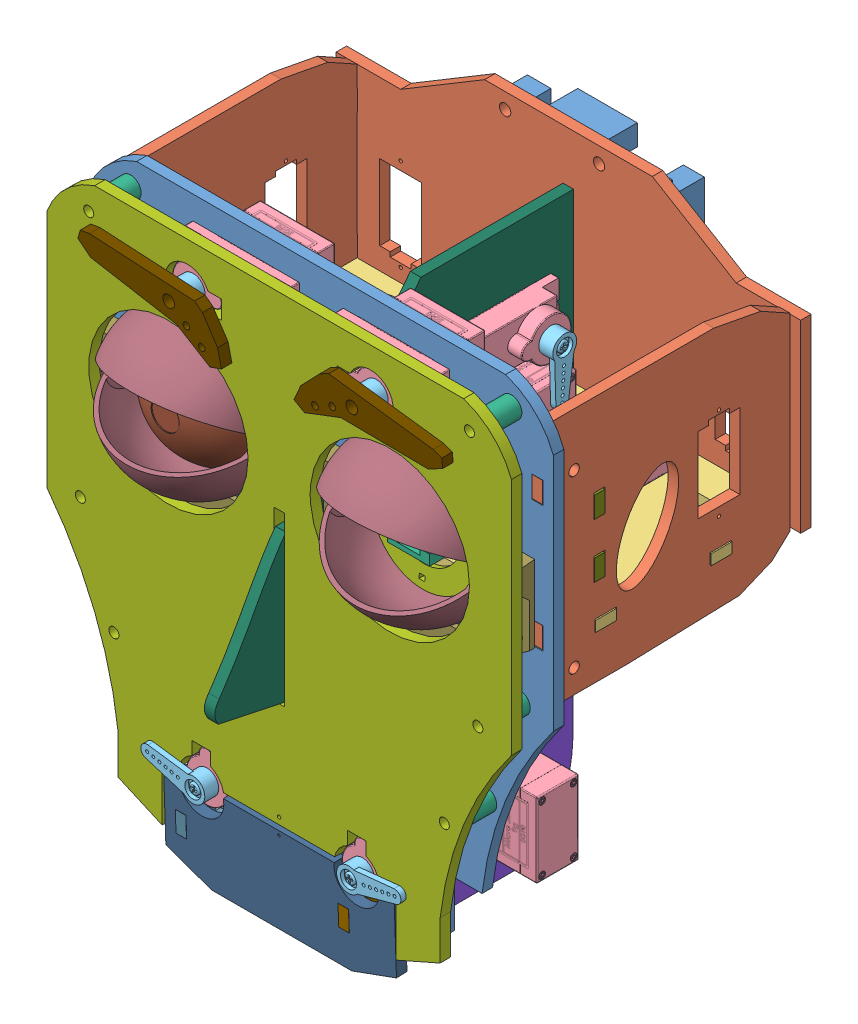
SolidWorks assembly Assembly_skullbox, configuration Default. Lengths in mm.
Overall size (140.72 167.86 124.87).
78 component instances, 31 part files, 174 mates.
Components (placement in the parent):
- faceFrameBack-1: faceFrameBack [Default] at (-18.3406 54.7458 -27.5154) size (140.72 156.7 3.18)
- skullbox_side-1: skullbox_side [Default] at (-85.5236 10.1688 -63.3929) size (3.18 75.04 78.21)
- skullbox_bottom-1: skullbox_bottom [Default] at (-18.3406 -15.2312 -64.0914) size (134.47 3.18 65.53)
- SG90 BODY-1: SG90 BODY [Default] at (-44.9852 -5.3125 -69.5016) x (0 0 1) z (-1 0 0) size (32.36 29.6 12.65)
- SG90 ARM-1: SG90 ARM [Default] at (-51.2844 1.5836 -75.8008) x (0.999363 0 -0.035696) z (0.035696 0 0.999363) size (19.74 4.23 7.24)
- SG90 BODY-2: SG90 BODY [Default] at (-34.4188 -5.3125 -64.2438) size (32.36 29.6 12.65)
- SG90 ARM-2: SG90 ARM [Default] at (-40.718 1.5836 -57.9446) x (0.976821 0 -0.214059) z (0.214059 0 0.976821) size (19.74 4.23 7.24)
- spacer_#6thread_3_4trlong-1: spacer_#6thread_3_4trlong [93330A443] at (-75.9986 47.1258 -19.5779) x (0.813395 0.581711 0) z (0 0 1) size (6.35 6.35 10.62)
- spacer_#6thread_3_4trlong-2: spacer_#6thread_3_4trlong [93330A443] at (-68.3786 -59.5542 -19.5779) size (6.35 6.35 10.62)
- spacer_#6thread_3_4trlong-3: spacer_#6thread_3_4trlong [93330A443] at (39.3174 47.1258 -19.5779) size (6.35 6.35 10.62)
- spacer_#6thread_3_4trlong-4: spacer_#6thread_3_4trlong [93330A443] at (31.6974 -59.5542 -19.5779) x (-0.161594 -0.986857 0) z (0 0 1) size (6.35 6.35 10.62)
- faceFrameFront-1: faceFrameFront [Default] at (-18.3406 54.7458 -14.8154) size (140.72 157.48 3.18)
- spacer_#6thread_3_4trlong-5: spacer_#6thread_3_4trlong [93330A443] at (41.8574 -29.0742 -19.5779) size (6.35 6.35 10.62)
- spacer_#6thread_3_4trlong-6: spacer_#6thread_3_4trlong [93330A443] at (-78.5386 -29.0742 -19.5779) size (6.35 6.35 10.62)
- SG90 BODY-4: SG90 BODY [Default] at (-52.3824 35.0825 -17.5967) x (-1 0.000928 0) z (0.000928 1 0) size (32.36 29.6 12.65)
- skullBoxMandible-3: skullBoxMandible [Default] at (13.4602 -65.9042 -46.5654) size (3.18 63.5 41.33)
- SG90 BODY-5: SG90 BODY [Default] at (6.7165 -91.99 -42.222) x (0 -1 0) z (0 0 -1) size (32.36 29.6 12.65)
- SG90 ARM-3: SG90 ARM [Default] at (-0.7384 -85.6908 -48.5212) x (0 0.917715 0.397239) z (0 -0.397239 0.917715) size (19.74 4.23 7.24)
- jawbone3-1: jawbone3 [Default] at (-0.7384 -85.6908 -48.5212) x (1 0 0) z (0 -0.034208 0.999415) size (3.18 31.5 43.99)
- jawFront-1: jawFront [Default] at (-18.382 -95.8718 -15.0679) x (1 0 0) z (0 -0.034208 0.999415) size (69.85 26.67 3.17)
- skullbox_side-2: skullbox_side [Default] at (45.6166 10.4228 -63.3929) size (3.18 75.04 78.21)
- SG90 BODY-7: SG90 BODY [Default] at (-26.6972 -9.0082 -87.6372) x (0 0 -1) z (0 1 0) size (32.36 29.6 12.65)
- SG90 ARM-5: SG90 ARM [Default] at (-33.5933 -2.709 -81.338) x (0 -0.999683 0.025167) z (0 -0.025167 -0.999683) size (19.74 4.23 7.24)
- SG90 BODY-8: SG90 BODY [Default] at (-10.0348 20.1002 -87.6372) x (0 0 -1) z (0 -1 0) size (32.36 29.6 12.65)
- SG90 ARM-6: SG90 ARM [Default] at (-3.1387 13.801 -81.338) x (0 0.998641 -0.052121) z (0 -0.052121 -0.998641) size (19.74 4.23 7.24)
- skullBoxMandibleRight-3: skullBoxMandibleRight [Default] at (-53.2656 -65.9042 -46.5654) size (3.18 63.5 41.33)
- jawCrossBeam-2: jawCrossBeam [Default] at (-23.7889 -100.3419 -40.0004) x (1 0 0) z (0 -0.034208 0.999415) size (52.55 11.43 3.17)
- mandibleBack-2: mandibleBack [Default] at (-18.3406 -51.2992 -62.3896) size (69.95 34.29 3.18)
- SG90 BODY-9: SG90 BODY [Default] at (11.5298 -92.5742 -17.5967) x (0 -1 0) z (-1 0 0) size (32.36 29.6 12.65)
- SG90 ARM-7: SG90 ARM [Default] at (5.2306 -86.275 -10.7006) x (-0.983188 -0.182597 0) z (-0.182597 0.983188 0) size (19.74 4.23 7.24)
- jawboneRight-1: jawboneRight [Default] at (-50.0144 -85.6908 -48.5212) x (1 0 0) z (0 -0.034208 0.999415) size (3.17 31.94 43.99)
- SG90 BODY-10: SG90 BODY [Default] at (-35.6126 -92.5742 -17.5967) x (0 -1 0) z (-1 0 0) size (32.36 29.6 12.65)
- SG90 ARM-8: SG90 ARM [Default] at (-41.9118 -86.275 -10.7006) x (0.976458 -0.215708 0) z (-0.215708 -0.976458 0) size (19.74 4.23 7.24)
- skullBoxNosePanel-1: skullBoxNosePanel [Default] at (-19.9535 13.3438 -63.5199) size (3.18 90.94 112.09)
- skullbox_firewall-1: skullbox_firewall [Default] at (-18.2771 6.9938 -43.0602) size (134.37 41.33 3.18)
- angleBracket_4_40screwThread-1: angleBracket_4_40screwThread [Default] at (41.1335 30.6132 -27.5154) x (0.999994 -0.003567 0) z (0 0 -1) size (8.71 6.35 9.53)
- angleBracket_4_40screwThread-2: angleBracket_4_40screwThread [Default] at (-77.8147 30.6158 -27.5154) x (-1 0 0) z (0 0 -1) size (8.71 6.35 9.53)
- angleBracket_4_40screwThread-3: angleBracket_4_40screwThread [Default] at (41.1335 -21.4542 -27.5154) x (1 0 0) z (0 0 -1) size (8.71 6.35 9.53)
- angleBracket_4_40screwThread-4: angleBracket_4_40screwThread [Default] at (-77.8147 -21.4542 -27.5154) x (-1 0 0) z (0 0 -1) size (8.71 6.35 9.53)
- angleBracket_4_40screwThread-5: angleBracket_4_40screwThread [Default] at (20.9913 -50.6642 -27.5154) x (-1 0 0) z (0 0 -1) size (8.71 6.35 9.53)
- angleBracket_4_40screwThread-6: angleBracket_4_40screwThread [Default] at (-57.6725 -50.6642 -27.5154) x (1 0 0) z (0 0 -1) size (8.71 6.35 9.53)
- SG90 BODY-11: SG90 BODY [Default] at (15.6896 47.5793 -17.5967) x (1 0.000928 0) z (0.000928 -1 0) size (32.36 29.6 12.65)
- SG90 ARM-9: SG90 ARM [Default] at (-46.0773 41.3759 -10.7006) x (-0.81658 0.577232 0) z (0.577232 0.81658 0) size (19.74 4.23 7.24)
- SG90 ARM-10: SG90 ARM [Default] at (9.3963 41.2743 -10.7006) x (0.907777 0.419454 0) z (0.419454 -0.907777 0) size (19.74 4.23 7.24)
- eyebrow-1: eyebrow [Default] at (-51.4817 40.5048 -9.0877) x (0.960868 -0.277008 0) z (0 0 1) size (45.26 13.1 3.17)
- eyebrow-2: eyebrow [Default] at (14.5528 39.4369 -5.9127) x (-0.995184 -0.098029 0) z (0 0 -1) size (45.26 13.1 3.17)
- unoKitBoard-1: unoKitBoard [Default] at (-18.3181 17.1284 -102.4454) x (0 1 0) z (0 0 -1) size (72.06 53.59 12.95)
- skullbox_back-2: skullbox_back [Default] at (-18.3406 10.8038 -102.4454) size (140.72 79.4 3.18)
- gearLargeB-1: gearLargeB [Default] at (-62.9176 -70.1452 -73.0314) x (0 0 1) z (-1 0 0) size (48.61 57.77 3.18)
- gearLargeNoTabs-1: gearLargeNoTabs [Default] at (-59.7426 -70.1452 -73.0314) x (0 0 1) z (-1 0 0) size (45.38 54.54 3.17)
- spacerNeckTilt-1: spacerNeckTilt [Default] at (-59.7426 -42.4092 -45.2954) size (3.17 25.4 25.4)
- gearLargeNoTabs-2: gearLargeNoTabs [Default] at (-66.0926 -70.1452 -73.0314) x (0 0 1) z (-1 0 0) size (45.38 54.54 3.17)
- Assembly_eyeWithStraighPullParts-3: Assembly_eyeWithStraighPullParts [Default] at (-52.8322 6.1704 -29.3385) x (-1 0 0) z (0 0 1) size (36.66 36.54 29.79)
  - eyeBracket_straightPull-1: eyeBracket_straightPull [Default] at (-1.0272 -6.7924 0.7563) size (19.05 12.95 22.61)
  - eyeRing_straightPull-1: eyeRing_straightPull [Default] at (-1.1034 -0.1884 5.7083) x (0.999925 0 0.012279) z (-0.012279 -0.002177 0.999922) size (33.02 35.56 7.15)
  - clevisPin_cored-1: clevisPin_cored [Default] at (-1.0272 -8.1259 5.7093) x (0.999925 0 0.012279) z (0 1 0) size (9.65 9.65 18.35)
  - eyeXAxisRod-1: eyeXAxisRod [Default] at (-17.6121 -0.1884 5.5056) x (0.999925 0 0.012279) z (-0.012279 0 0.999925) size (33.02 2.34 2.34)
  - spacer_1_4trlong-1: spacer_1_4trlong [94639A705] at (5.6017 -0.1884 5.7907) x (-0.004447 -0.932122 0.362118) z (-0.999925 0 -0.012279) size (4.76 4.76 6.91)
  - spacer_1_4trlong-2: spacer_1_4trlong [94639A705] at (-7.8085 -0.1884 5.626) x (-0.012279 0 0.999925) z (-0.999925 0 -0.012279) size (4.76 4.76 6.91)
  - eye-1: eye [Default] at (-1.1131 -0.1901 6.502) x (0.999701 0.021124 0.012322) z (-0.012279 -0.002177 0.999922) size (35.76 35.76 12.49)
- SG90 BODY-12: SG90 BODY [Default] at (-2.5926 -5.3125 -51.747) x (-1 0 0) z (0 0 -1) size (32.36 29.6 12.65)
- SG90 BODY-13: SG90 BODY [Default] at (20.8008 -5.3125 -69.1714) x (0 0 1) z (-1 0 0) size (32.36 29.6 12.65)
- SG90 ARM-11: SG90 ARM [Default] at (3.7066 1.5836 -58.0462) x (-0.998428 0 -0.05604) z (0.05604 0 -0.998428) size (19.74 4.23 7.24)
- SG90 ARM-12: SG90 ARM [Default] at (14.5016 1.5836 -75.4706) x (-0.999964 0 -0.008467) z (0.008467 0 -0.999964) size (19.74 4.23 7.24)
- spacer_1_4trlong-1: spacer_1_4trlong [94639A705] at (8.4722 6.6128 -23.8353) x (-0.030396 0 0.999538) z (-0.999538 0 -0.030396) size (4.76 4.76 6.91)
- eyeBracket_straightPull-1: eyeBracket_straightPull [Default] at (15.2509 0.0088 -28.5822) size (19.05 12.95 22.61)
- eyeRing_straightPull-1: eyeRing_straightPull [Default] at (15.1748 6.6128 -23.6315) x (0.999538 0 0.030396) z (-0.030272 0.090239 0.99546) size (33.02 35.56 7.15)
- clevisPin_cored-1: clevisPin_cored [Default] at (15.2509 -1.3247 -23.6292) x (0.999538 0 0.030396) z (0 1 0) size (9.65 9.65 18.35)
- eyeXAxisRod-1: eyeXAxisRod [Default] at (-1.3276 6.6128 -24.1334) x (0.999538 0 0.030396) z (-0.030396 0 0.999538) size (33.02 2.34 2.34)
- spacer_1_4trlong-2: spacer_1_4trlong [94639A705] at (21.8773 6.6128 -23.4277) x (-0.030396 0 0.999538) z (-0.999538 0 -0.030396) size (4.76 4.76 6.91)
- eye-1: eye [Default] at (15.1507 6.6844 -22.8414) x (-0.843364 -0.536849 0.023019) z (-0.030272 0.090239 0.99546) size (35.76 35.76 12.49) (hidden)
- Assembly_Eyelid_StraightPullParts-1: Assembly_Eyelid_StraightPullParts [Default] at (-51.0341 -8.3385 -21.5988) size (62.38 64.85 38.25)
  - eyeLidMount_B-1: eyeLidMount_B [Default] at (-0.8344 -17.1797 -2.7416) x (-1 0 0) z (0 0 1) size (62.38 36.2 5.33)
  - eyelidA-2: eyelidA [Default] at (-1.4136 14.8243 0.4334) x (0 0.463125 0.886293) z (-1 0 0) size (27.73 27.4 48.41)
  - eyelidA-3: eyelidA [Default] at (-1.1646 14.8243 0.4334) x (0 -0.332285 0.943179) z (1 0 0) size (27.73 27.4 48.41)
- eyeLidMount_B-1: eyeLidMount_B [Default] at (15.1874 -25.5182 -24.3404) x (-1 0 0) z (0 0 1) size (62.38 36.2 5.33)
- eyelidA-1: eyelidA [Default] at (14.6083 6.4858 -21.1654) x (0 0.456477 0.889735) z (-1 0 0) size (27.73 27.4 48.41)
- eyelidA-2: eyelidA [Default] at (14.8572 6.4858 -21.1654) x (0 -0.518383 0.855148) z (1 0 0) size (27.73 27.4 48.41)
Mates (geometry in assembly coordinates):
- Coincident15: coincident anti-aligned: plane of skullbox_bottom-1 through (-57.5836 -15.2313 -92.0314) normal (1 0 0); plane of SG90 BODY-1 through (-57.5836 -5.3125 -69.5016) normal (-1 0 0)
- Coincident16: coincident anti-aligned: plane of skullbox_bottom-1 through (-44.8836 -15.2313 -92.0314) normal (0 0 1); plane of SG90 BODY-1 through (-57.5836 -27.8169 -92.0314) normal (0 0 -1)
- Coincident17: coincident anti-aligned: plane of skullbox_bottom-1 through (45.6674 -12.0562 -94.3174) normal (0 1 0); plane of SG90 BODY-1 through (-57.5836 -12.0562 -64.5867) normal (0 -1 0)
- Concentric11: concentric aligned: cylinder of SG90 BODY-1 through (-51.2844 37.8563 -75.8008) axis (0 -1 0) radius 2.286; cylinder of SG90 ARM-1 through (-51.2844 1.3042 -75.8008) axis (0 -1 0) radius 2.286
- Coincident18: coincident anti-aligned: plane of SG90 BODY-1 through (-57.5836 -1.0326 -69.5016) normal (0 1 0); plane of SG90 ARM-1 through (-51.2844 -1.0326 -75.8008) normal (0 -1 0)
- Coincident19: coincident anti-aligned: plane of skullbox_bottom-1 through (-56.9486 -15.2313 -51.6454) normal (0 0 -1); plane of SG90 BODY-2 through (-34.4188 -5.3125 -51.6454) normal (0 0 1)
- Coincident20: coincident anti-aligned: plane of skullbox_bottom-1 through (-56.9486 -15.2313 -64.3454) normal (1 0 0); plane of SG90 BODY-2 through (-56.9486 -27.8169 -51.6454) normal (-1 0 0)
- Coincident21: coincident anti-aligned: plane of skullbox_bottom-1 through (45.6674 -12.0562 -94.3174) normal (0 1 0); plane of SG90 BODY-2 through (-29.5039 -12.0562 -51.6454) normal (0 -1 0)
- Concentric12: concentric aligned: cylinder of SG90 BODY-2 through (-40.718 37.8563 -57.9446) axis (0 -1 0) radius 2.286; cylinder of SG90 ARM-2 through (-40.718 1.3042 -57.9446) axis (0 -1 0) radius 2.286
- Coincident22: coincident anti-aligned: plane of SG90 BODY-2 through (-34.4188 -1.0326 -51.6454) normal (0 1 0); plane of SG90 ARM-2 through (-40.718 -1.0326 -57.9446) normal (0 -1 0)
- Coincident29: coincident anti-aligned: plane of faceFrameBack-1 through (-85.5236 26.0438 -27.5154) normal (0 1 0); plane of skullbox_side-1 through (-82.3486 26.0438 -24.2896) normal (0 -1 0)
- Coincident30: coincident anti-aligned: plane of faceFrameBack-1 through (-85.5236 26.0438 -27.5154) normal (1 0 0); plane of skullbox_side-1 through (-85.5236 38.7438 -27.5154) normal (-1 0 0)
- Coincident31: coincident anti-aligned: plane of faceFrameBack-1 through (-88.6986 -84.9542 -27.5154) normal (0 0 -1); plane of skullbox_side-1 through (-82.3486 -18.4062 -27.5154) normal (0 0 1)
- Concentric13: concentric aligned: cylinder of faceFrameBack-1 through (-75.9986 47.1258 -27.5154) axis (0 0 1) radius 1.524; cone of spacer_#6thread_3_4trlong-1 through (-75.9986 47.1258 -24.3404) axis (0 0 1)
- Coincident35: coincident anti-aligned: plane of faceFrameBack-1 through (-88.6986 -84.9542 -24.3404) normal (0 0 1); plane of spacer_#6thread_3_4trlong-1 through (-75.9986 47.1258 -24.3404) normal (0 0 -1)
- Concentric14: concentric anti-aligned: cylinder of faceFrameBack-1 through (-68.3786 -59.5542 -27.5154) axis (0 0 1) radius 1.524; circle of spacer_#6thread_3_4trlong-2
- Coincident36: coincident anti-aligned: plane of faceFrameBack-1 through (-88.6986 -84.9542 -24.3404) normal (0 0 1); plane of spacer_#6thread_3_4trlong-2 through (-68.3786 -59.5542 -24.3404) normal (0 0 -1)
- Concentric15: concentric anti-aligned: cylinder of faceFrameBack-1 through (31.6974 -59.5542 -27.5154) axis (0 0 1) radius 1.524; circle of spacer_#6thread_3_4trlong-4
- Coincident37: coincident anti-aligned: plane of faceFrameBack-1 through (-88.6986 -84.9542 -24.3404) normal (0 0 1); plane of spacer_#6thread_3_4trlong-4 through (31.6974 -59.5542 -24.3404) normal (0 0 -1)
- Concentric16: concentric anti-aligned: cylinder of faceFrameBack-1 through (39.3174 47.1258 -27.5154) axis (0 0 1) radius 1.524; circle of spacer_#6thread_3_4trlong-3
- Coincident38: coincident anti-aligned: plane of faceFrameBack-1 through (-88.6986 -84.9542 -24.3404) normal (0 0 1); plane of spacer_#6thread_3_4trlong-3 through (39.3174 47.1258 -24.3404) normal (0 0 -1)
- Concentric17: concentric anti-aligned: circle of spacer_#6thread_3_4trlong-3; cylinder of faceFrameFront-1 through (39.3174 47.1258 -14.8154) axis (0 0 1) radius 1.524
- Coincident39: coincident anti-aligned: plane of spacer_#6thread_3_4trlong-3 through (39.3174 47.1258 -14.8154) normal (0 0 1); plane of faceFrameFront-1 through (-88.6986 -84.9542 -14.8154) normal (0 0 -1)
- Concentric18: concentric anti-aligned: circle of spacer_#6thread_3_4trlong-4; cylinder of faceFrameFront-1 through (31.6974 -59.5542 -14.8154) axis (0 0 1) radius 1.524
- Concentric19: concentric anti-aligned: cylinder of faceFrameFront-1 through (-78.5386 -29.0742 -14.8154) axis (0 0 1) radius 1.524; circle of spacer_#6thread_3_4trlong-6
- Coincident40: coincident anti-aligned: plane of faceFrameFront-1 through (-88.6986 -84.9542 -14.8154) normal (0 0 -1); plane of spacer_#6thread_3_4trlong-6 through (-78.5386 -29.0742 -14.8154) normal (0 0 1)
- Concentric20: concentric anti-aligned: cylinder of faceFrameBack-1 through (41.8574 -29.0742 -27.5154) axis (0 0 1) radius 1.524; circle of spacer_#6thread_3_4trlong-5
- Coincident41: coincident anti-aligned: plane of faceFrameBack-1 through (-88.6986 -84.9542 -24.3404) normal (0 0 1); plane of spacer_#6thread_3_4trlong-5 through (41.8574 -29.0742 -24.3404) normal (0 0 -1)
- Coincident45: coincident anti-aligned: plane of faceFrameBack-1 through (-52.3736 44.5059 -27.5154) normal (1 -0.000928 0); plane of SG90 BODY-4 through (-52.3707 47.6809 -24.3404) normal (-1 0.000928 0)
- Coincident46: coincident anti-aligned: plane of faceFrameBack-1 through (-29.5107 47.6597 -27.5154) normal (-0.000928 -1 0); plane of SG90 BODY-4 through (-52.3707 47.6809 -17.5967) normal (0.000928 1 0)
- Coincident47: coincident anti-aligned: plane of faceFrameBack-1 through (-88.6986 -84.9542 -24.3404) normal (0 0 1); plane of SG90 BODY-4 through (-57.2856 47.6855 -24.3404) normal (0 0 -1)
- Coincident50: coincident anti-aligned: plane of faceFrameBack-1 through (-88.6986 -84.9542 -27.5154) normal (0 0 -1); plane of skullBoxMandible-3 through (16.6352 -97.6542 -27.5154) normal (0 0 1)
- Coincident102: coincident anti-aligned: plane of faceFrameBack-1 through (48.8424 32.6478 -27.5154) normal (0 -1 0); plane of skullbox_side-2 through (48.7916 32.6478 -27.5154) normal (0 1 0)
- Coincident103: coincident anti-aligned: plane of faceFrameBack-1 through (45.6166 26.0438 -27.5154) normal (1 0 0); plane of skullbox_side-2 through (45.6166 38.9978 -27.5154) normal (-1 0 0)
- Coincident104: coincident anti-aligned: plane of faceFrameBack-1 through (-88.6986 -84.9542 -27.5154) normal (0 0 -1); plane of skullbox_side-2 through (48.7916 -18.1522 -27.5154) normal (0 0 1)
- Concentric31: concentric aligned: cylinder of SG90 BODY-7 through (-69.866 -2.709 -81.338) axis (1 0 0) radius 2.286; cylinder of SG90 ARM-5 through (-33.3139 -2.709 -81.338) axis (1 0 0) radius 2.286
- Coincident118: coincident anti-aligned: plane of SG90 BODY-7 through (-30.9771 3.5902 -87.6372) normal (-1 0 0); plane of SG90 ARM-5 through (-30.9771 -2.709 -81.338) normal (1 0 0)
- Coincident119: coincident anti-aligned: plane of skullbox_side-1 through (-82.3485 -15.2312 -46.6924) normal (0 1 0); plane of skullbox_bottom-1 through (45.6674 -15.2312 -94.3174) normal (0 -1 0)
- Coincident120: coincident anti-aligned: plane of skullbox_side-1 through (-82.3485 -15.2312 -40.2154) normal (0 0 -1); plane of skullbox_bottom-1 through (-82.3486 -15.2312 -40.2154) normal (0 0 1)
- Coincident121: coincident anti-aligned: plane of skullbox_side-1 through (-82.3486 38.7438 -27.5154) normal (1 0 0); plane of skullbox_bottom-1 through (-82.3486 -12.0562 -33.8654) normal (-1 0 0)
- Concentric32: concentric aligned: cylinder of SG90 BODY-8 through (33.134 13.801 -81.338) axis (-1 0 0) radius 2.286; cylinder of SG90 ARM-6 through (-3.4181 13.801 -81.338) axis (-1 0 0) radius 2.286
- Coincident127: coincident anti-aligned: plane of SG90 BODY-8 through (-5.7549 7.5018 -87.6372) normal (1 0 0); plane of SG90 ARM-6 through (-5.7549 13.801 -81.338) normal (-1 0 0)
- Coincident137: coincident anti-aligned: plane of faceFrameBack-1 through (13.4094 -72.2542 -27.5154) normal (0 1 0); plane of skullBoxMandible-3 through (13.4602 -72.2542 -27.5154) normal (0 -1 0)
- Coincident138: coincident anti-aligned: plane of faceFrameBack-1 through (16.6352 -72.2542 -27.5154) normal (-1 0 0); plane of skullBoxMandible-3 through (16.6352 -34.1542 -65.6154) normal (1 0 0)
- Coincident139: coincident anti-aligned: plane of skullBoxMandible-3 through (13.4602 -69.4602 -54.8204) normal (0 0 1); plane of SG90 BODY-5 through (6.7165 -91.99 -54.8204) normal (0 0 -1)
- Coincident140: coincident anti-aligned: plane of skullBoxMandible-3 through (13.4602 -69.4602 -54.8204) normal (0 -1 0); plane of SG90 BODY-5 through (29.2209 -69.4602 -54.8204) normal (0 1 0)
- Coincident141: coincident anti-aligned: plane of skullBoxMandible-3 through (13.4602 -34.1542 -65.6154) normal (-1 0 0); plane of SG90 BODY-5 through (13.4602 -96.9049 -54.8204) normal (1 0 0)
- Coincident151: coincident anti-aligned: plane of faceFrameBack-1 through (-50.0906 -72.2542 -27.5154) normal (0 1 0); plane of skullBoxMandibleRight-3 through (-53.2656 -72.2542 -27.5154) normal (0 -1 0)
- Coincident152: coincident anti-aligned: plane of faceFrameBack-1 through (-50.0906 -65.6502 -27.5154) normal (-1 0 0); plane of skullBoxMandibleRight-3 through (-50.0906 -34.1542 -65.6154) normal (1 0 0)
- Coincident153: coincident anti-aligned: plane of faceFrameBack-1 through (-88.6986 -84.9542 -27.5154) normal (0 0 -1); plane of skullBoxMandibleRight-3 through (-50.0906 -97.6542 -27.5154) normal (0 0 1)
- Coincident158: coincident anti-aligned: plane of skullBoxMandibleRight-3 through (-53.2656 -62.0942 -59.1638) normal (0 1 0); plane of mandibleBack-2 through (-53.3164 -62.0942 -62.3896) normal (0 -1 0)
- Coincident159: coincident anti-aligned: plane of skullBoxMandibleRight-3 through (-53.2656 -55.7442 -62.3896) normal (0 0 1); plane of mandibleBack-2 through (13.4094 -34.1542 -62.3896) normal (0 0 -1)
- Coincident160: coincident anti-aligned: plane of skullBoxMandibleRight-3 through (-50.0906 -34.1542 -65.6154) normal (1 0 0); plane of mandibleBack-2 through (-50.0906 -68.4442 -59.2146) normal (-1 0 0)
- Concentric46: concentric aligned: cylinder of SG90 BODY-5 through (-36.4523 -85.6908 -48.5212) axis (1 0 0) radius 2.286; cylinder of SG90 ARM-3 through (-0.459 -85.6908 -48.5212) axis (1 0 0) radius 2.286
- Coincident169: coincident anti-aligned: plane of faceFrameBack-1 through (-88.6986 -84.9542 -24.3404) normal (0 0 1); plane of SG90 BODY-9 through (-1.0686 -97.4891 -24.3404) normal (0 0 -1)
- Concentric47: concentric aligned: cylinder of SG90 BODY-9 through (5.2306 -86.275 25.5721) axis (0 0 -1) radius 2.286; cylinder of SG90 ARM-7 through (5.2306 -86.275 -10.98) axis (0 0 -1) radius 2.286
- Coincident171: coincident anti-aligned: plane of SG90 BODY-9 through (-1.0686 -92.5742 -13.3168) normal (0 0 1); plane of SG90 ARM-7 through (5.2306 -86.275 -13.3168) normal (0 0 -1)
- Concentric49: concentric anti-aligned: cylinder of SG90 ARM-3 through (-2.3513 -85.6908 -48.5212) axis (1 0 0) radius 3.6195; cylinder of jawbone3-1 through (2.4366 -85.6908 -48.5212) axis (-1 0 0) radius 3.937
- Coincident174: coincident anti-aligned: plane of SG90 ARM-3 through (-0.7384 -85.6908 -48.5212) normal (1 0 0); plane of jawbone3-1 through (-0.7384 -93.2914 -41.7923) normal (-1 0 0)
- Coincident178: coincident anti-aligned: plane of jawbone3-1 through (-0.7384 -93.2914 -41.7923) normal (-1 0 0); plane of jawCrossBeam-2 through (-0.7384 -106.1621 -37.0227) normal (1 0 0)
- Coincident182: coincident anti-aligned: plane of faceFrameBack-1 through (-1.0686 -69.7142 -27.5155) normal (1 0 0); plane of SG90 BODY-9 through (-1.0686 -92.5742 -17.5967) normal (-1 0 0)
- Concentric51: concentric aligned: cylinder of jawbone3-1 through (2.4366 -85.6908 -48.5212) axis (-1 0 0) radius 3.937; cylinder of jawboneRight-1 through (-46.8394 -85.6908 -48.5212) axis (-1 0 0) radius 3.175
- Coincident186: coincident anti-aligned: plane of SG90 BODY-5 through (2.4366 -91.99 -54.8204) normal (-1 0 0); plane of jawbone3-1 through (2.4366 -93.2914 -41.7923) normal (1 0 0)
- Coincident189: coincident anti-aligned: plane of faceFrameBack-1 through (-45.1376 -92.5742 -27.5155) normal (0 1 0); plane of SG90 BODY-10 through (-48.211 -92.5742 -24.3404) normal (0 -1 0)
- Coincident190: coincident anti-aligned: plane of faceFrameBack-1 through (-35.6126 -69.7142 -27.5155) normal (-1 0 0); plane of SG90 BODY-10 through (-35.6126 -92.5742 -17.5967) normal (1 0 0)
- Coincident191: coincident anti-aligned: plane of faceFrameBack-1 through (-88.6986 -84.9542 -24.3404) normal (0 0 1); plane of SG90 BODY-10 through (-48.211 -97.4891 -24.3404) normal (0 0 -1)
- Concentric52: concentric aligned: cylinder of SG90 BODY-10 through (-41.9118 -86.275 25.5721) axis (0 0 -1) radius 2.286; cylinder of SG90 ARM-8 through (-41.9118 -86.275 -10.98) axis (0 0 -1) radius 2.286
- Coincident192: coincident anti-aligned: plane of SG90 BODY-10 through (-48.211 -92.5742 -13.3168) normal (0 0 1); plane of SG90 ARM-8 through (-41.9118 -86.275 -13.3168) normal (0 0 -1)
- Coincident193: coincident anti-aligned: plane of faceFrameBack-1 through (-1.0686 -92.5742 -27.5155) normal (0 1 0); plane of SG90 BODY-9 through (-1.0686 -92.5742 -24.3404) normal (0 -1 0)
- Coincident197: coincident anti-aligned: plane of skullbox_bottom-1 through (-19.9535 -15.2313 -75.2674) normal (1 0 0); plane of skullBoxNosePanel-1 through (-19.9535 38.7438 -99.3974) normal (-1 0 0)
- Coincident198: coincident anti-aligned: plane of skullbox_bottom-1 through (-19.9535 -15.2313 -81.6174) normal (0 0 1); plane of skullBoxNosePanel-1 through (-19.9535 -15.282 -81.6174) normal (0 0 -1)
- Coincident199: coincident anti-aligned: plane of skullbox_bottom-1 through (45.6674 -12.0562 -94.3174) normal (0 1 0); plane of skullBoxNosePanel-1 through (-16.7785 -12.0562 -27.6424) normal (0 -1 0)
- Coincident200: coincident anti-aligned: plane of skullbox_bottom-1 through (-55.1071 -15.2312 -43.0602) normal (0 0 1); plane of skullbox_firewall-1 through (45.7309 26.0438 -43.0602) normal (0 0 -1)
- Coincident201: coincident anti-aligned: plane of skullbox_bottom-1 through (-48.6301 -15.2312 -39.8344) normal (-1 0 0); plane of skullbox_firewall-1 through (-48.6301 -12.0562 -43.0602) normal (1 0 0)
- Coincident202: coincident anti-aligned: plane of skullbox_bottom-1 through (45.6674 -12.0562 -94.3174) normal (0 1 0); plane of skullbox_firewall-1 through (-82.2851 -12.0562 -39.8852) normal (0 -1 0)
- Coincident203: coincident anti-aligned: plane of jawbone3-1 through (2.4366 -103.2032 -12.0911) normal (0 -0.999415 -0.034208); plane of jawFront-1 through (-0.7892 -103.0929 -15.3151) normal (0 0.999415 0.034208)
- Coincident204: coincident anti-aligned: plane of jawbone3-1 through (2.4366 -93.2914 -41.7923) normal (1 0 0); plane of jawFront-1 through (2.4366 -96.7466 -15.0978) normal (-1 0 0)
- Coincident205: coincident anti-aligned: plane of jawbone3-1 through (2.4366 -94.2081 -15.0109) normal (0 -0.034208 0.999415); plane of jawFront-1 through (16.543 -86.3523 -14.7421) normal (0 0.034208 -0.999415)
- Coincident206: coincident anti-aligned: plane of jawFront-1 through (-50.071 -103.0929 -15.3151) normal (0 0.999415 0.034208); plane of jawboneRight-1 through (-46.8394 -103.2032 -12.0911) normal (0 -0.999415 -0.034208)
- Concentric53: concentric aligned: cylinder of SG90 ARM-3 through (1.8778 -96.9612 -53.3997) axis (-1 0 0) radius 0.4636; cylinder of jawbone3-1 through (2.4366 -96.9612 -53.3997) axis (-1 0 0) radius 0.4445
- Coincident207: coincident anti-aligned: plane of jawCrossBeam-2 through (-50.0652 -103.6236 -36.9359) normal (0 -0.999415 -0.034208); plane of jawboneRight-1 through (-46.8394 -103.5133 -40.1598) normal (0 0.999415 0.034208)
- Coincident208: coincident anti-aligned: plane of jawCrossBeam-2 through (-0.7384 -94.7388 -36.6318) normal (0 -0.034208 0.999415); plane of jawboneRight-1 through (-46.8394 -97.2773 -36.7186) normal (0 0.034208 -0.999415)
- Concentric54: concentric anti-aligned: cylinder of faceFrameBack-1 through (40.4096 30.6158 -27.5154) axis (0 0 1) radius 1.5875; cylinder of angleBracket_4_40screwThread-1 through (40.4096 30.6158 -27.5154) axis (0 0 -1) radius 1.1176
- Coincident209: coincident anti-aligned: plane of faceFrameBack-1 through (-88.6986 -84.9542 -27.5154) normal (0 0 -1); plane of angleBracket_4_40screwThread-1 through (45.4783 27.4227 -27.5154) normal (0 0 1)
- Concentric61: concentric anti-aligned: cylinder of faceFrameBack-1 through (-77.0908 30.6158 -27.5154) axis (0 0 1) radius 1.5875; cylinder of angleBracket_4_40screwThread-2 through (-77.0908 30.6158 -27.5154) axis (0 0 -1) radius 1.1176
- Coincident213: coincident anti-aligned: plane of faceFrameBack-1 through (-88.6986 -84.9542 -27.5154) normal (0 0 -1); plane of angleBracket_4_40screwThread-2 through (-82.1708 33.7908 -27.5154) normal (0 0 1)
- Parallel1: parallel anti-aligned: plane of skullbox_side-1 through (-82.3486 38.7438 -27.5154) normal (1 0 0); plane of angleBracket_4_40screwThread-2 through (-82.1708 27.4408 -29.0902) normal (-1 0 0)
- Concentric63: concentric anti-aligned: cylinder of faceFrameBack-1 through (40.4096 -21.4542 -27.5154) axis (0 0 1) radius 1.5875; cylinder of angleBracket_4_40screwThread-3 through (40.4096 -21.4542 -27.5154) axis (0 0 -1) radius 1.1176
- Coincident215: coincident anti-aligned: plane of faceFrameBack-1 through (-88.6986 -84.9542 -27.5154) normal (0 0 -1); plane of angleBracket_4_40screwThread-3 through (45.4896 -24.6292 -27.5154) normal (0 0 1)
- Parallel2: parallel anti-aligned: plane of skullbox_side-2 through (45.6166 38.9978 -27.5154) normal (-1 0 0); plane of angleBracket_4_40screwThread-3 through (45.4896 -18.2792 -29.0902) normal (1 0 0)
- Concentric64: concentric anti-aligned: cylinder of faceFrameBack-1 through (-77.0908 -21.4542 -27.5154) axis (0 0 1) radius 1.5875; cylinder of angleBracket_4_40screwThread-4 through (-77.0908 -21.4542 -27.5154) axis (0 0 -1) radius 1.1176
- Coincident217: coincident anti-aligned: plane of faceFrameBack-1 through (-88.6986 -84.9542 -27.5154) normal (0 0 -1); plane of angleBracket_4_40screwThread-4 through (-82.1708 -18.2792 -27.5154) normal (0 0 1)
- Parallel3: parallel anti-aligned: plane of skullbox_side-1 through (-82.3486 38.7438 -27.5154) normal (1 0 0); plane of angleBracket_4_40screwThread-4 through (-82.1708 -24.6292 -29.0902) normal (-1 0 0)
- Concentric66: concentric anti-aligned: cylinder of faceFrameBack-1 through (21.7152 -50.6642 -27.5155) axis (0 0 1) radius 1.5875; cylinder of angleBracket_4_40screwThread-5 through (21.7152 -50.6642 -27.5154) axis (0 0 -1) radius 1.1176
- Coincident220: coincident anti-aligned: plane of faceFrameBack-1 through (-88.6986 -84.9542 -27.5154) normal (0 0 -1); plane of angleBracket_4_40screwThread-5 through (16.6352 -47.4892 -27.5154) normal (0 0 1)
- Coincident221: coincident anti-aligned: plane of skullBoxMandible-3 through (16.6352 -34.1542 -65.6154) normal (1 0 0); plane of angleBracket_4_40screwThread-5 through (16.6352 -53.8392 -29.0902) normal (-1 0 0)
- Concentric67: concentric anti-aligned: cylinder of faceFrameBack-1 through (-58.3964 -50.6642 -27.5155) axis (0 0 1) radius 1.5875; cylinder of angleBracket_4_40screwThread-6 through (-58.3964 -50.6642 -27.5154) axis (0 0 -1) radius 1.1176
- Coincident222: coincident anti-aligned: plane of faceFrameBack-1 through (-88.6986 -84.9542 -27.5154) normal (0 0 -1); plane of angleBracket_4_40screwThread-6 through (-53.3164 -53.8392 -27.5154) normal (0 0 1)
- Parallel4: parallel anti-aligned: plane of skullBoxMandibleRight-3 through (-53.2656 -34.1542 -65.6154) normal (-1 0 0); plane of angleBracket_4_40screwThread-6 through (-53.3164 -47.4892 -29.0902) normal (1 0 0)
- Coincident224: coincident anti-aligned: plane of faceFrameBack-1 through (15.7013 34.9809 -27.5154) normal (-1 -0.000928 0); plane of SG90 BODY-11 through (15.7013 34.9809 -24.3404) normal (1 0.000928 0)
- Coincident225: coincident anti-aligned: plane of faceFrameBack-1 through (-7.1587 34.9597 -27.5154) normal (-0.000928 1 0); plane of SG90 BODY-11 through (15.7013 34.9809 -17.5967) normal (0.000928 -1 0)
- Coincident226: coincident anti-aligned: plane of faceFrameBack-1 through (-88.6986 -84.9542 -24.3404) normal (0 0 1); plane of SG90 BODY-11 through (20.6162 34.9855 -24.3404) normal (0 0 -1)
- Concentric70: concentric aligned: cylinder of SG90 BODY-11 through (9.3963 41.2743 25.5721) axis (0 0 -1) radius 2.286; cylinder of SG90 ARM-10 through (9.3963 41.2743 -10.98) axis (0 0 -1) radius 2.286
- Coincident228: coincident anti-aligned: plane of SG90 BODY-11 through (15.7013 34.9809 -13.3168) normal (0 0 1); plane of SG90 ARM-10 through (9.3963 41.2743 -13.3168) normal (0 0 -1)
- Concentric72: concentric aligned: circle of SG90 ARM-9; circle of eyebrow-1
- Concentric73: concentric aligned: circle of SG90 ARM-9; circle of eyebrow-1
- Coincident229: coincident anti-aligned: plane of SG90 ARM-9 through (-46.0773 41.3759 -9.0877) normal (0 0 1); plane of eyebrow-1 through (-74.2299 41.8295 -9.0877) normal (0 0 -1)
- Concentric74: concentric aligned: cylinder of SG90 BODY-4 through (-46.0773 41.3759 25.5721) axis (0 0 -1) radius 2.286; cylinder of SG90 ARM-9 through (-46.0773 41.3759 -10.98) axis (0 0 -1) radius 2.286
- Coincident230: coincident anti-aligned: plane of SG90 BODY-4 through (-52.3707 47.6809 -13.3168) normal (0 0 1); plane of SG90 ARM-9 through (-46.0773 41.3759 -13.3168) normal (0 0 -1)
- Concentric75: concentric anti-aligned: cylinder of SG90 ARM-10 through (9.3963 41.2743 -10.2434) axis (0 0 1) radius 2.4447; cylinder of eyebrow-2 through (9.3963 41.2743 -5.9127) axis (0 0 -1) radius 1.778
- Concentric76: concentric anti-aligned: cylinder of SG90 ARM-10 through (3.4359 38.5202 -13.3168) axis (0 0 1) radius 0.4636; cylinder of eyebrow-2 through (3.4359 38.5202 -5.9127) axis (0 0 -1) radius 1.016
- Coincident231: coincident anti-aligned: plane of SG90 ARM-10 through (9.3963 41.2743 -9.0877) normal (0 0 1); plane of eyebrow-2 through (37.1637 36.6113 -9.0877) normal (0 0 -1)
- Concentric77: concentric aligned: cylinder of unoKitBoard-1 through (-42.5751 -3.1662 -102.4454) axis (0 0 -1) radius 1.5875; cylinder of skullbox_back-2 through (-42.5751 -3.1662 -99.2704) axis (0 0 -1) radius 1.7145
- Concentric78: concentric aligned: cylinder of unoKitBoard-1 through (-37.4951 49.234 -102.4454) axis (0 0 -1) radius 1.7145; cylinder of skullbox_back-2 through (-37.4951 49.234 -99.2704) axis (0 0 -1) radius 1.7145
- Coincident238: coincident anti-aligned: plane of unoKitBoard-1 through (8.4789 51.4438 -102.4454) normal (0 0 1); plane of skullbox_back-2 through (52.0174 38.7438 -102.4454) normal (0 0 -1)
- Coincident239: coincident anti-aligned: plane of skullbox_side-1 through (-82.3486 -12.0562 -102.4962) normal (0 -1 0); plane of skullbox_back-2 through (-85.5236 -12.0562 -102.4454) normal (0 1 0)
- Coincident240: coincident anti-aligned: plane of skullbox_side-1 through (-85.5236 38.7438 -27.5154) normal (-1 0 0); plane of skullbox_back-2 through (-85.5236 -5.7062 -102.4454) normal (1 0 0)
- Coincident241: coincident anti-aligned: plane of skullbox_side-1 through (-82.3486 -18.4062 -99.2704) normal (0 0 -1); plane of skullbox_back-2 through (52.0174 38.7438 -99.2704) normal (0 0 1)
- Concentric79: concentric aligned: cylinder of skullBoxMandibleRight-3 through (-53.2656 -42.4092 -45.2954) axis (1 0 0) radius 3.2385; cylinder of gearLargeB-1 through (-66.0926 -42.4092 -45.2954) axis (1 0 0) radius 3.2385
- Coincident242: coincident anti-aligned: plane of skullbox_bottom-1 through (45.6674 -15.2312 -94.3174) normal (0 -1 0); plane of gearLargeB-1 through (-62.9176 -15.2312 -26.8055) normal (0 1 0)
- Concentric80: concentric aligned: cylinder of gearLargeB-1 through (-66.0926 -42.4092 -45.2954) axis (1 0 0) radius 3.2385; cylinder of gearLargeNoTabs-1 through (-62.9176 -42.4092 -45.2954) axis (1 0 0) radius 3.2385
- Coincident243: coincident anti-aligned: plane of skullbox_bottom-1 through (45.6674 -15.2312 -94.3174) normal (0 -1 0); plane of gearLargeNoTabs-1 through (-59.7426 -15.2312 -26.8055) normal (0 1 0)
- Coincident244: coincident anti-aligned: plane of gearLargeB-1 through (-62.9176 -46.0871 -21.7246) normal (1 0 0); plane of gearLargeNoTabs-1 through (-62.9176 -46.0871 -21.7246) normal (-1 0 0)
- Concentric81: concentric anti-aligned: cylinder of gearLargeB-1 through (-66.0926 -42.4092 -45.2954) axis (1 0 0) radius 3.2385; cylinder of spacerNeckTilt-1 through (-56.5676 -42.4092 -45.2954) axis (-1 0 0) radius 3.175
- Coincident245: coincident anti-aligned: plane of gearLargeNoTabs-1 through (-59.7426 -46.0871 -21.7246) normal (1 0 0); plane of spacerNeckTilt-1 through (-59.7426 -42.4092 -45.2954) normal (-1 0 0)
- Concentric83: concentric aligned: cylinder of gearLargeB-1 through (-66.0926 -42.4092 -45.2954) axis (1 0 0) radius 3.2385; cylinder of gearLargeNoTabs-2 through (-69.2676 -42.4092 -45.2954) axis (1 0 0) radius 3.2385
- Coincident248: coincident anti-aligned: plane of skullbox_bottom-1 through (45.6674 -15.2312 -94.3174) normal (0 -1 0); plane of gearLargeNoTabs-2 through (-66.0926 -15.2312 -26.8055) normal (0 1 0)
- Coincident249: coincident anti-aligned: plane of gearLargeB-1 through (-66.0926 -46.0871 -21.7246) normal (-1 0 0); plane of gearLargeNoTabs-2 through (-66.0926 -46.0871 -21.7246) normal (1 0 0)
- Coincident250: coincident anti-aligned: plane of skullbox_bottom-1 through (-66.0926 -15.2314 -63.3294) normal (1 0 0); plane of gearLargeB-1 through (-66.0926 -46.0871 -21.7246) normal (-1 0 0)
- Concentric89: concentric: cylinder of skullbox_firewall-1 through (-47.9951 6.4858 -43.0602) axis (0 0 1) radius 1.397; cylinder of Assembly_eyeWithStraighPullParts-3/eyeBracket_straightPull-1 through (-45.7091 6.4858 -39.8852) axis (0 0 -1) radius 1.7145
- Concentric90: concentric: cylinder of skullbox_firewall-1 through (-55.6151 6.4858 -43.0602) axis (0 0 1) radius 1.397; cylinder of Assembly_eyeWithStraighPullParts-3/eyeBracket_straightPull-1 through (-57.9011 6.4858 -39.8852) axis (0 0 -1) radius 1.7145
- Coincident254: coincident anti-aligned: plane of skullbox_firewall-1 through (45.7309 26.0438 -39.8852) normal (0 0 1); plane of Assembly_eyeWithStraighPullParts-3/eyeBracket_straightPull-1 through (-45.4551 0.0088 -39.8852) normal (0 0 -1)
- Coincident255: coincident anti-aligned: plane of jawCrossBeam-2 through (-46.8394 -106.1621 -37.0227) normal (-1 0 0); plane of jawboneRight-1 through (-46.8394 -93.2914 -41.7923) normal (1 0 0)
- Coincident257: coincident anti-aligned: plane of skullbox_bottom-1 through (20.2674 -15.2313 -64.3454) normal (0 0 1); plane of SG90 BODY-12 through (-2.5926 -5.3125 -64.3454) normal (0 0 -1)
- Coincident258: coincident anti-aligned: plane of skullbox_bottom-1 through (-2.5926 -15.2313 -54.8204) normal (1 0 0); plane of SG90 BODY-12 through (-2.5926 -12.0562 -64.3454) normal (-1 0 0)
- Coincident259: coincident anti-aligned: plane of skullbox_bottom-1 through (45.6674 -12.0562 -94.3174) normal (0 1 0); plane of SG90 BODY-12 through (-7.5075 -12.0562 -64.3454) normal (0 -1 0)
- Coincident260: coincident anti-aligned: plane of skullbox_bottom-1 through (8.2024 -15.2313 -92.0314) normal (1 0 0); plane of SG90 BODY-13 through (8.2024 -5.3125 -69.1714) normal (-1 0 0)
- Coincident261: coincident anti-aligned: plane of skullbox_bottom-1 through (17.7274 -15.2313 -69.1714) normal (0 0 -1); plane of SG90 BODY-13 through (8.2024 -12.0562 -69.1714) normal (0 0 1)
- Coincident262: coincident anti-aligned: plane of skullbox_bottom-1 through (45.6674 -12.0562 -94.3174) normal (0 1 0); plane of SG90 BODY-13 through (8.2024 -12.0562 -64.2565) normal (0 -1 0)
- Concentric91: concentric aligned: cylinder of SG90 BODY-12 through (3.7066 37.8563 -58.0462) axis (0 -1 0) radius 2.286; cylinder of SG90 ARM-11 through (3.7066 1.3042 -58.0462) axis (0 -1 0) radius 2.286
- Coincident263: coincident anti-aligned: plane of SG90 BODY-12 through (-2.5926 -1.0326 -64.3454) normal (0 1 0); plane of SG90 ARM-11 through (3.7066 -1.0326 -58.0462) normal (0 -1 0)
- Concentric92: concentric aligned: cylinder of SG90 BODY-13 through (14.5016 37.8563 -75.4706) axis (0 -1 0) radius 2.286; cylinder of SG90 ARM-12 through (14.5016 1.3042 -75.4706) axis (0 -1 0) radius 2.286
- Coincident264: coincident anti-aligned: plane of SG90 BODY-13 through (8.2024 -1.0326 -69.1714) normal (0 1 0); plane of SG90 ARM-12 through (14.5016 -1.0326 -75.4706) normal (0 -1 0)
- Coincident265: coincident anti-aligned: plane of SG90 BODY-7 through (-4.1928 3.5902 -65.1074) normal (0 0 1); plane of skullBoxNosePanel-1 through (-16.7784 -9.0082 -65.1074) normal (0 0 -1)
- Coincident266: coincident anti-aligned: plane of SG90 BODY-7 through (-26.6972 -9.0082 -87.6372) normal (0 -1 0); plane of skullBoxNosePanel-1 through (-16.7784 -9.0082 -65.1074) normal (0 1 0)
- Coincident267: coincident anti-aligned: plane of SG90 BODY-7 through (-19.9535 3.5902 -92.5521) normal (1 0 0); plane of skullBoxNosePanel-1 through (-19.9535 38.7438 -99.3974) normal (-1 0 0)
- Coincident268: coincident anti-aligned: plane of SG90 BODY-8 through (-32.5392 7.5018 -65.1074) normal (0 0 1); plane of skullBoxNosePanel-1 through (-16.7784 7.5018 -65.1074) normal (0 0 -1)
- Coincident269: coincident anti-aligned: plane of SG90 BODY-8 through (-10.0348 7.5018 -87.6372) normal (0 -1 0); plane of skullBoxNosePanel-1 through (-16.7784 7.5018 -65.1074) normal (0 1 0)
- Coincident270: coincident anti-aligned: plane of SG90 BODY-8 through (-16.7785 7.5018 -92.5521) normal (-1 0 0); plane of skullBoxNosePanel-1 through (-16.7785 38.7438 -99.3974) normal (1 0 0)
- Concentric93: concentric anti-aligned: cylinder of eyeBracket_straightPull-1 through (15.2509 12.9628 -23.6292) axis (0 -1 0) radius 3.4925; cylinder of clevisPin_cored-1 through (15.2509 -2.8487 -23.6292) axis (0 1 0) radius 3.175
- Coincident271: coincident anti-aligned: plane of eyeBracket_straightPull-1 through (8.9009 12.9628 -17.2792) normal (0 1 0); plane of clevisPin_cored-1 through (15.2509 12.9628 -23.6292) normal (0 -1 0)
- Concentric94: concentric aligned: cylinder of clevisPin_cored-1 through (18.4244 6.6128 -23.5327) axis (-0.999538 0 -0.030396) radius 1.27; cylinder of eyeXAxisRod-1 through (31.6771 6.6128 -23.1297) axis (-0.999538 0 -0.030396) radius 1.1684
- Concentric95: concentric anti-aligned: cylinder of eyeRing_straightPull-1 through (-1.3276 6.6128 -24.1334) axis (0.999538 0 0.030396) radius 1.1938; cylinder of eyeXAxisRod-1 through (31.6771 6.6128 -23.1297) axis (-0.999538 0 -0.030396) radius 1.1684
- Coincident272: coincident aligned: plane of eyeRing_straightPull-1 through (31.6771 6.6128 -23.1297) normal (0.999538 0 0.030396); plane of eyeXAxisRod-1 through (31.6771 6.6128 -23.1297) normal (0.999538 0 0.030396)
- Concentric96: concentric anti-aligned: cylinder of spacer_1_4trlong-1 through (5.0194 6.6128 -23.9403) axis (0.999538 0 0.030396) radius 1.143; cylinder of eyeXAxisRod-1 through (31.6771 6.6128 -23.1297) axis (-0.999538 0 -0.030396) radius 1.1684
- Coincident273: coincident anti-aligned: plane of spacer_1_4trlong-1 through (5.0194 6.6128 -23.9403) normal (-0.999538 0 -0.030396); plane of eyeRing_straightPull-1 through (5.0194 6.6128 -23.9403) normal (0.999538 0 0.030396)
- Concentric97: concentric anti-aligned: cylinder of eyeXAxisRod-1 through (31.6771 6.6128 -23.1297) axis (-0.999538 0 -0.030396) radius 1.1684; cylinder of spacer_1_4trlong-2 through (18.4244 6.6128 -23.5327) axis (0.999538 0 0.030396) radius 1.143
- Coincident274: coincident anti-aligned: plane of eyeRing_straightPull-1 through (25.3301 6.6128 -23.3227) normal (-0.999538 0 -0.030396); plane of spacer_1_4trlong-2 through (25.3301 6.6128 -23.3227) normal (0.999538 0 0.030396)
- Tangent1: tangent anti-aligned: cylinder of clevisPin_cored-1 through (15.2509 -2.8487 -23.6292) axis (0 1 0) radius 3.175; plane of spacer_1_4trlong-2 through (18.4244 6.6128 -23.5327) normal (-0.999538 0 -0.030396)
- Concentric98: concentric: cylinder of skullbox_firewall-1 through (19.0609 6.4858 -43.0603) axis (0 0 1) radius 1.397; cylinder of eyeBracket_straightPull-1 through (21.3469 6.4858 -39.8852) axis (0 0 -1) radius 1.7145
- Concentric99: concentric: cylinder of skullbox_firewall-1 through (11.4409 6.4858 -43.0603) axis (0 0 1) radius 1.397; cylinder of eyeBracket_straightPull-1 through (9.1549 6.4858 -39.8852) axis (0 0 -1) radius 1.7145
- Concentric100: concentric aligned: circle of eyeRing_straightPull-1; circle of eye-1
- Coincident275: coincident anti-aligned: plane of eyeRing_straightPull-1 through (15.1507 6.6844 -22.8414) normal (-0.030272 0.090239 0.99546); plane of eye-1 through (15.1507 6.6844 -22.8414) normal (0.030272 -0.090239 -0.99546)
- Concentric101: concentric aligned: cylinder of faceFrameBack-1 through (-79.2498 -10.2782 -27.5154) axis (0 0 1) radius 1.524; cylinder of Assembly_Eyelid_StraightPullParts-1/eyeLidMount_B-1 through (-79.2498 -10.2782 -24.3404) axis (0 0 1) radius 1.7145
- Concentric102: concentric aligned: cylinder of faceFrameBack-1 through (-24.4874 -10.2782 -27.5154) axis (0 0 1) radius 1.524; cylinder of Assembly_Eyelid_StraightPullParts-1/eyeLidMount_B-1 through (-24.4874 -10.2782 -24.3404) axis (0 0 1) radius 1.7145
- Coincident276: coincident anti-aligned: plane of faceFrameBack-1 through (-88.6986 -84.9542 -24.3404) normal (0 0 1); plane of Assembly_Eyelid_StraightPullParts-1/eyeLidMount_B-1 through (-51.8686 -25.5182 -24.3404) normal (0 0 -1)
- Coincident278: coincident anti-aligned: plane of eyelidA-1 through (-7.1138 10.4407 -23.1944) normal (-1 0 0); plane of eyelidA-2 through (-7.1138 2.6847 -23.4696) normal (1 0 0)
- Concentric103: concentric aligned: cylinder of eyelidA-1 through (-9.7071 6.4858 -21.1654) axis (1 0 0) radius 1.3462; cylinder of eyelidA-2 through (-8.3838 6.4858 -21.1654) axis (1 0 0) radius 1.3462
- Concentric104: concentric aligned: cylinder of eyeLidMount_B-1 through (-9.6538 6.4858 -21.1654) axis (1 0 0) radius 0.8255; cylinder of eyelidA-2 through (-8.3838 6.4858 -21.1654) axis (1 0 0) radius 1.3462
- Coincident279: coincident anti-aligned: plane of eyeLidMount_B-1 through (-8.3838 10.6768 -17.9904) normal (1 0 0); plane of eyelidA-2 through (-8.3838 6.4858 -21.1654) normal (-1 0 0)
- Concentric105: concentric aligned: cylinder of faceFrameBack-1 through (42.5686 -10.2782 -27.5154) axis (0 0 1) radius 1.524; cylinder of eyeLidMount_B-1 through (42.5686 -10.2782 -24.3404) axis (0 0 1) radius 1.7145
- Concentric106: concentric aligned: cylinder of faceFrameBack-1 through (-12.1938 -10.2782 -27.5154) axis (0 0 1) radius 1.524; cylinder of eyeLidMount_B-1 through (-12.1938 -10.2782 -24.3404) axis (0 0 1) radius 1.7145
- Coincident281: coincident anti-aligned: plane of faceFrameBack-1 through (-88.6986 -84.9542 -24.3404) normal (0 0 1); plane of eyeLidMount_B-1 through (15.1874 -25.5182 -24.3404) normal (0 0 -1)
- Coincident282: coincident anti-aligned: plane of skullbox_firewall-1 through (45.7309 26.0438 -39.8852) normal (0 0 1); plane of eyeBracket_straightPull-1 through (8.9009 12.9628 -39.8852) normal (0 0 -1)
